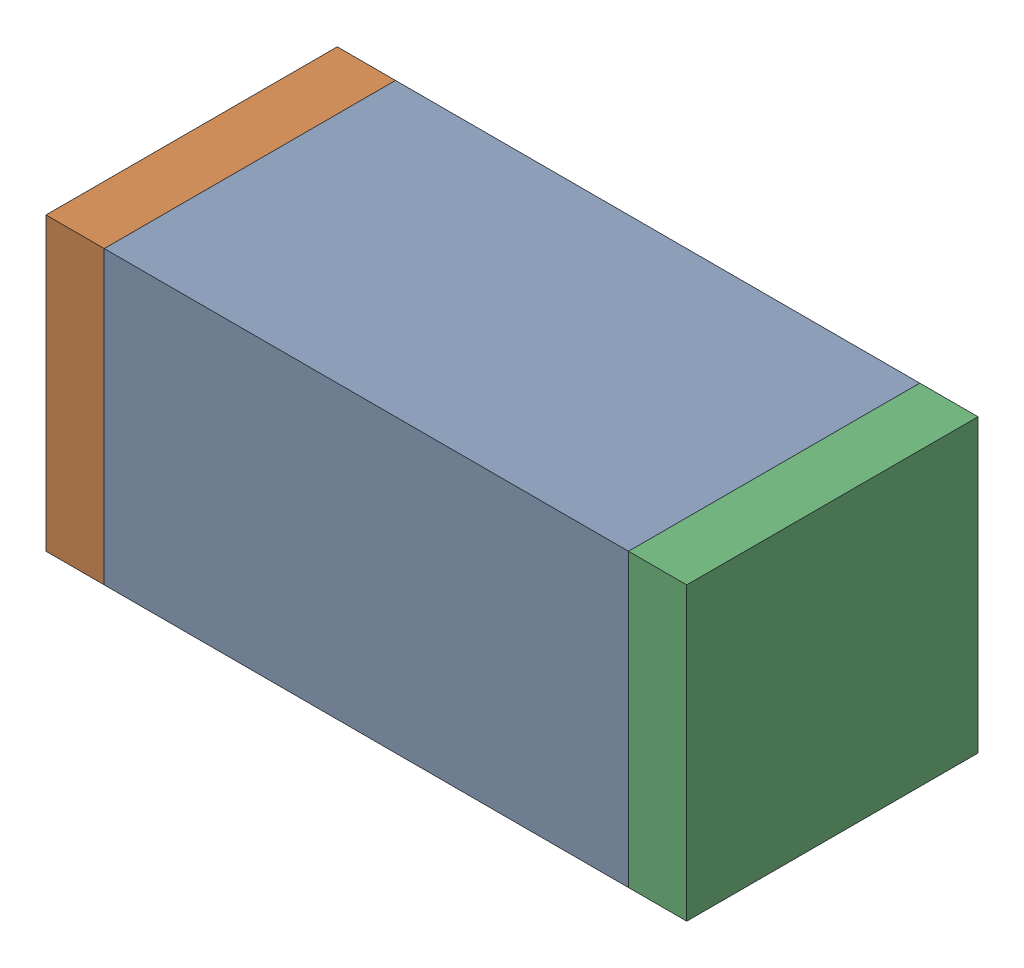
SolidWorks assembly C69, configuration Default. Lengths in mm.
Overall size (1.1 0.5 0.5).
6 component instances, 2 part files, 0 mates.
Components (placement in the parent):
- 836749680-1: 836749680 [Default] at (108.4 55.9 0) size (0.9 0.5 0.5)
  - Extruded_4-1: Extruded_4 [Default] at origin size (0.9 0.5 0.5)
- 810156080-1: 810156080 [Default] at (107.9 55.9 0) size (0.1 0.5 0.5)
  - Extruded_5-1: Extruded_5 [Default] at origin size (0.1 0.5 0.5)
- 810156080-2: 810156080 [Default] at (108.9 55.9 0) size (0.1 0.5 0.5)
  - Extruded_5-1: Extruded_5 [Default] at origin size (0.1 0.5 0.5)
